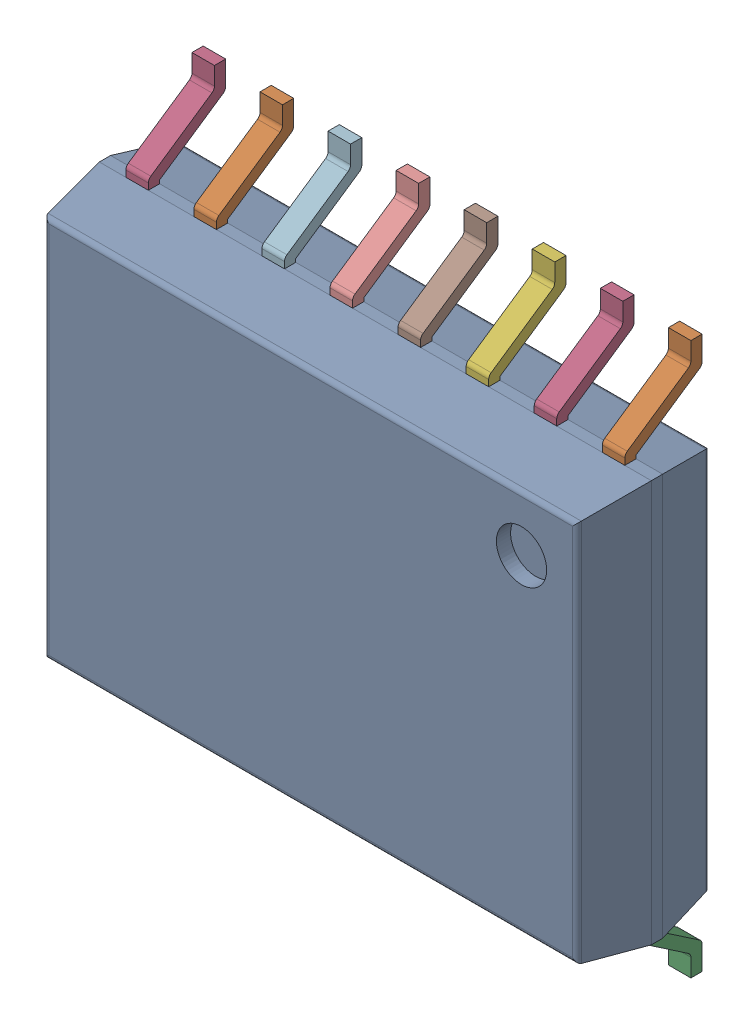
SolidWorks assembly IC5_1.step, configuration Default. Lengths in mm.
Overall size (10.3 10.3 2.65).
3 component instances, 2 part files, 0 mates.
Components (placement in the parent):
- 6383678080.step-1: 6383678080.step [Default] at (102.636 101.397 0) x (0 -1 0) z (0 0 1) size (10.3 10.3 2.65)
  - Body-0_3.step-14: Body-0_3.step [Default] at origin size (7.5 10.3 2.48)
  - PinsArrayLR_4.step-14: PinsArrayLR_4.step [Default] at origin size (10.3 9.31 1.44)
